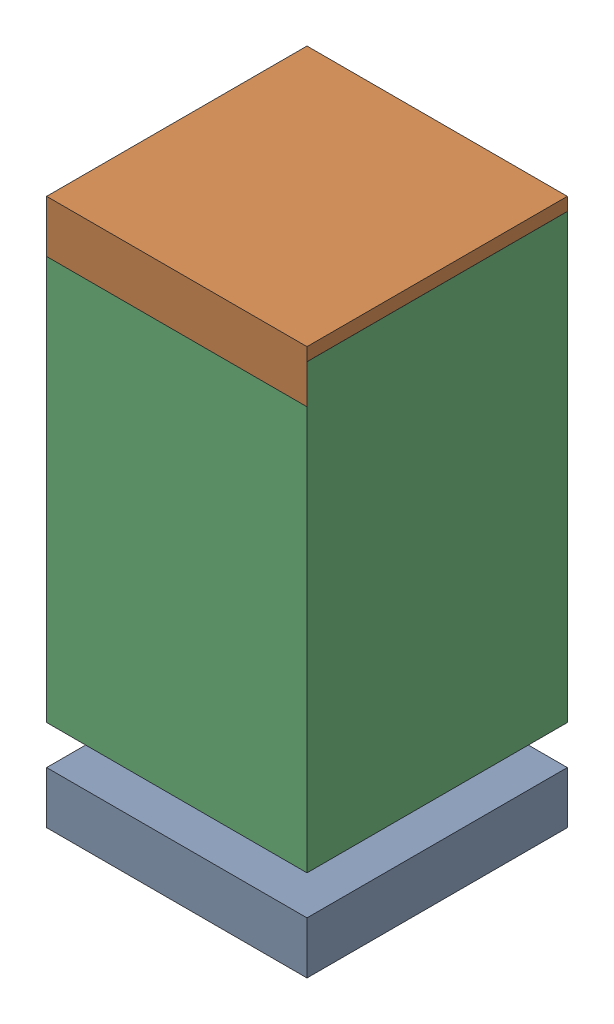
SolidWorks assembly C114, configuration Default. Lengths in mm.
Overall size (0.5 1.05 0.5).
6 component instances, 2 part files, 0 mates.
Components (placement in the parent):
- 810157360-1: 810157360 [Default] at (126.9 24.65 0) size (0.5 0.1 0.5)
  - Extruded_9-1: Extruded_9 [Default] at origin size (0.5 0.1 0.5)
- 810157360-2: 810157360 [Default] at (126.9 25.6 0) size (0.5 0.1 0.5)
  - Extruded_9-1: Extruded_9 [Default] at origin size (0.5 0.1 0.5)
- 810157104-1: 810157104 [Default] at (126.9001 25.1999 0) size (0.5 0.85 0.5)
  - Extruded_16-1: Extruded_16 [Default] at origin size (0.5 0.85 0.5)
